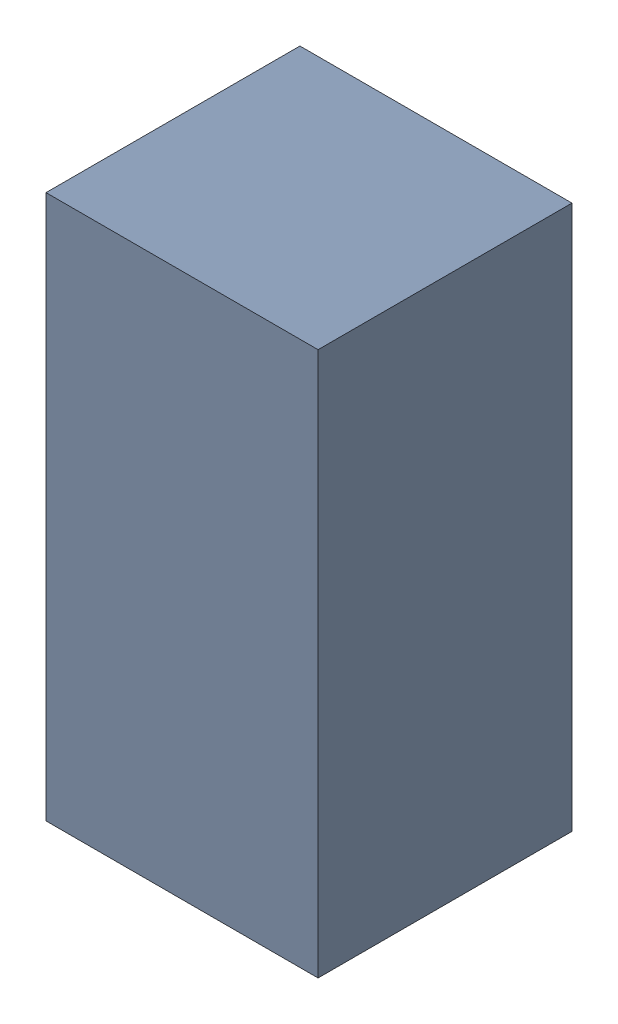
SolidWorks assembly NORKanaloa_v2.0.0_Power, configuration Default. Lengths in mm.
Overall size (1.5 3 1.4).
2 component instances, 1 part files, 0 mates.
Components (placement in the parent):
- 378153152-1: 378153152 [Default] at (91.525 61.075 -2.5524) size (1.5 3 1.4)
  - Extruded_1-1: Extruded_1 [Default] at origin size (1.5 3 1.4)
